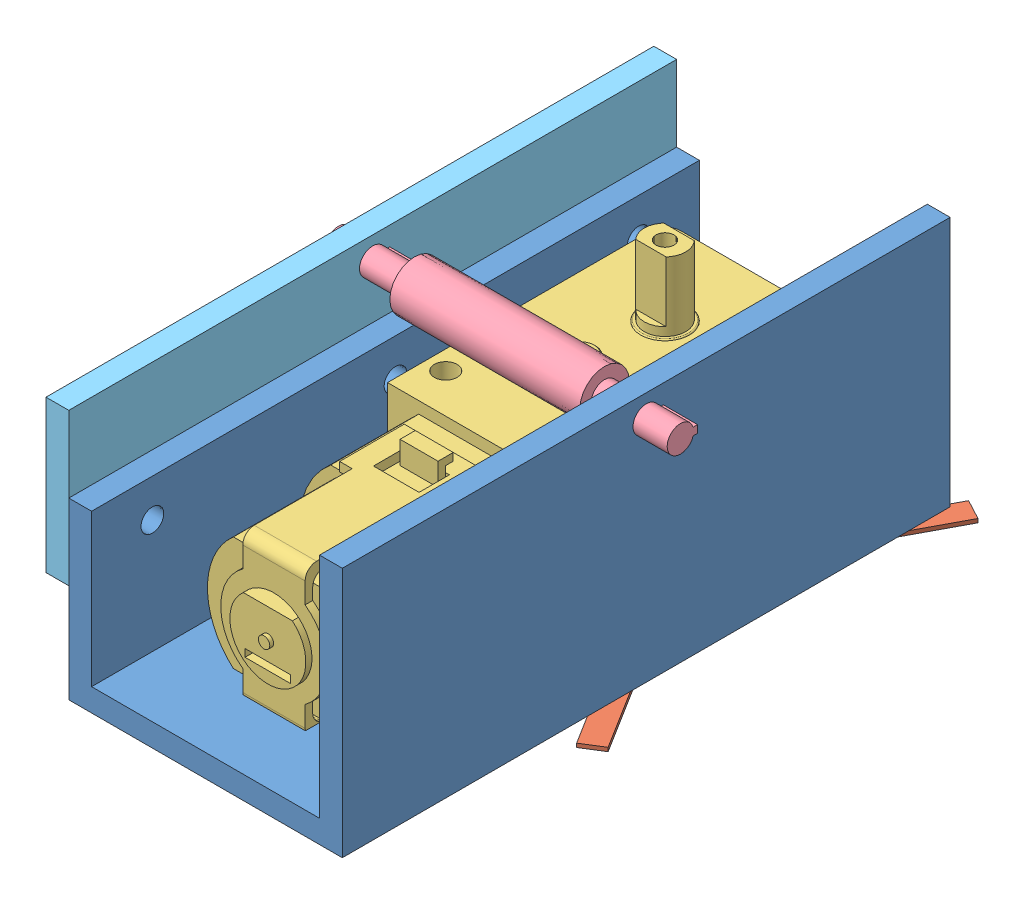
SolidWorks assembly tool_assembly, configuration Default. Lengths in mm.
Overall size (66.91 39.49 93.69).
6 component instances, 6 part files, 19 mates.
Components (placement in the parent):
- tool_casing-1: tool_casing [Default] at (25.653 23.4689 8.7727) size (36 33 80)
- blade-4: blade [Default] at (10.653 -12.7711 28.3027) x (0.469779 0 -0.882784) z (0.882784 0 0.469779) size (46.3 2 53.46)
- BO DC Motor-1: BO DC Motor [Default] at (10.653 5.9389 28.3027) size (22.5 37.42 69.3)
- connector-2: connector [Default] at (23.153 23.4689 48.7727) x (0 -1 0) z (0 0 -1) size (6.5 45 6.5)
- Part8^tool_assembly-1: Part8^tool_assembly [Default] at origin (virtual)
- assembley component-1: assembley component [Default] at (-10.347 6.4689 88.7727) x (0 0 -1) z (1 0 0) size (80 20 3)
Mates (geometry in assembly coordinates):
- Concentric1: concentric aligned: circle of tool_casing-1; circle of connector-1
- Width1: width aligned: plane of tool_casing-1 through (25.653 23.4689 90.7727) normal (0 0 -1); plane of tool_casing-1 through (25.653 23.4689 10.7727) normal (0 0 1); plane of connector-1 through (10.653 20.9689 38.2727) normal (0 0 -1); plane of connector-1 through (10.653 20.9689 63.2727) normal (0 0 1)
- Coincident5: coincident anti-aligned: plane of tool_casing-1 through (-4.347 -3.5311 86.7727) normal (0 1 0); plane of DC_Motor assembly-1 through (10.653 -3.5311 50.7727) normal (0 -1 0)
- Symmetric1: symmetric aligned: plane of tool_casing-1 through (25.653 -6.5311 10.7727) normal (1 0 0); plane of DC_Motor assembly-1 through (-4.347 23.4689 10.7727) normal (-1 0 0); plane of tool_casing-1 through (10.653 21.4689 50.7727) normal (-1 0 0)
- Symmetric2: symmetric aligned: plane of tool_casing-1 through (25.653 23.4689 88.7727) normal (0 0 1); plane of DC_Motor assembly-1 through (25.653 23.4689 8.7727) normal (0 0 -1); plane of tool_casing-1 through (10.653 21.4689 50.7727) normal (0 0 1)
- Concentric2: concentric anti-aligned: circle of DC_Motor assembly-1; circle of blade-4
- Coincident8: coincident aligned: plane of DC_Motor assembly-1 through (10.653 -12.5311 50.7727) normal (0 -1 0); plane of blade-4 through (10.653 -12.7711 28.3027) normal (0 -1 0)
- Coincident9: coincident anti-aligned: plane of tool_casing-1 through (-4.347 -3.5311 86.7727) normal (0 1 0); plane of Bo Motor With Wheel-1/Real Bo Motor With Wheel.STEP-1/Real Bo Motor Gear Box.STEP-1 through (4.0712 -3.5311 116.9285) normal (0 -1 0)
- Coincident10: coincident anti-aligned: plane of tool_casing-1 through (-4.347 -3.5311 86.7727) normal (0 1 0); plane of BO DC Motor-1 through (10.653 -3.5311 35.2727) normal (0 -1 0)
- Concentric3: concentric aligned: circle of blade-4; circle of BO DC Motor-1
- Coincident11: coincident aligned: plane of blade-4 through (10.653 -12.7711 28.3027) normal (0 -1 0); plane of BO DC Motor-1 through (10.653 -12.7711 28.3027) normal (0 -1 0)
- Width4: width anti-aligned: plane of BO DC Motor-1 through (21.903 5.9389 16.9727) normal (0 0 -1); plane of tool_casing-1 through (10.653 4.5789 80.5727) normal (0 0 1); plane of BO DC Motor-1 through (25.653 23.4689 88.7727) normal (0 0 1); plane of tool_casing-1 through (25.653 23.4689 8.7727) normal (0 0 -1)
- Width5: width aligned: plane of BO DC Motor-1 through (21.903 5.9389 53.5727) normal (1 0 0); plane of tool_casing-1 through (-0.597 5.9389 16.9727) normal (-1 0 0); plane of BO DC Motor-1 through (28.653 26.4689 88.7727) normal (1 0 0); plane of tool_casing-1 through (-7.347 26.4689 88.7727) normal (-1 0 0)
- Parallel1: parallel anti-aligned: plane of connector-2 through (23.153 23.4689 48.7727) normal (0 0 -1)
- Width6: width anti-aligned: plane of connector-2 through (33.153 23.4689 48.7727) normal (1 0 0); plane of tool_casing-1 through (-11.847 23.4689 48.7727) normal (-1 0 0); plane of connector-2 through (-7.347 26.4689 88.7727) normal (-1 0 0); plane of tool_casing-1 through (28.653 26.4689 88.7727) normal (1 0 0)
- Coincident15: coincident aligned: plane of tool_casing-1 through (25.653 26.4689 8.7727) normal (0 1 0); plane of assembley component-1 through (-7.347 26.4689 88.7727) normal (0 1 0)
- Coincident16: coincident anti-aligned: plane of tool_casing-1 through (-7.347 26.4689 88.7727) normal (-1 0 0); plane of assembley component-1 through (-7.347 6.4689 88.7727) normal (1 0 0)
- Coincident17: coincident aligned: plane of tool_casing-1 through (25.653 23.4689 8.7727) normal (0 0 -1); plane of assembley component-1 through (-7.347 6.4689 8.7727) normal (0 0 -1)
- Concentric9: concentric anti-aligned: cylinder of connector-2 through (-1.847 23.4689 48.7727) axis (1 0 0) radius 3.25; circle of assembley component-1
